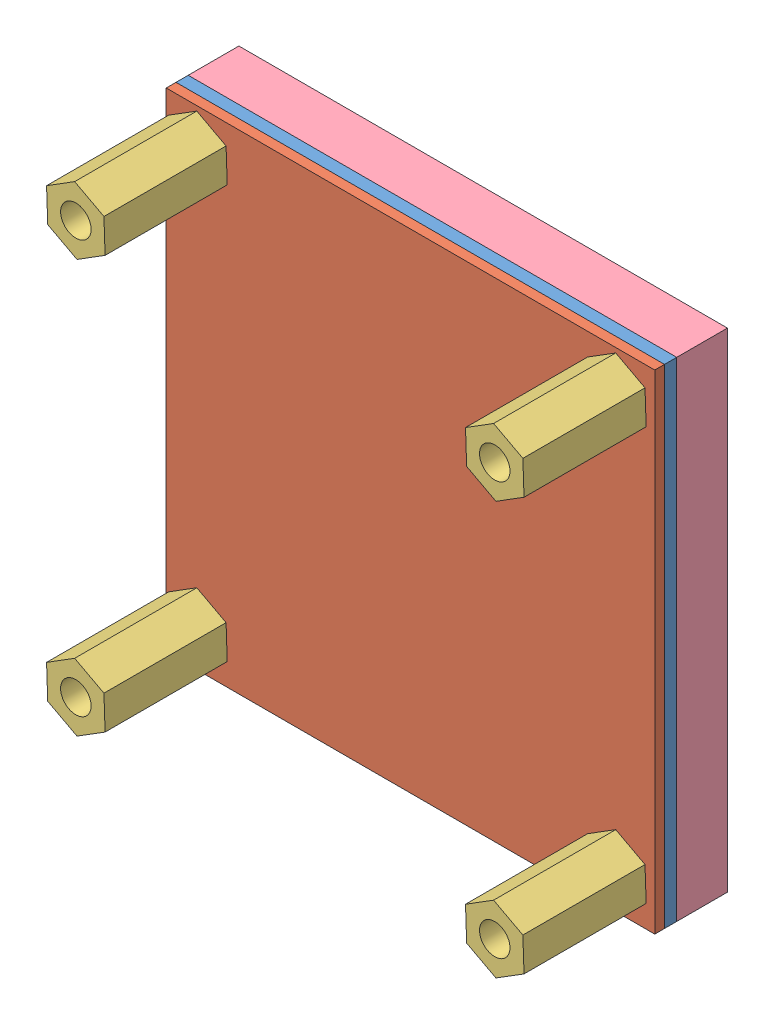
SolidWorks assembly EPM688_V2, configuration Default. Lengths in mm.
Overall size (40 40 16).
7 component instances, 4 part files, 14 mates.
Components (placement in the parent):
- 1559_B-1: 1559_B [Default] at (8.4797 17.3877 36.4763) size (40 40 1)
- pcb-1: pcb [Default] at (8.4797 17.3877 37.4763) size (40 40 0.8)
- standoff-1: standoff [Default] at (-8.9203 34.2877 48.2763) x (-1 0 0) z (0 0 -1) size (4.79 5.42 10)
- standoff-2: standoff [Default] at (-8.9203 0.4877 48.2763) x (-1 0 0) z (0 0 -1) size (4.79 5.42 10)
- standoff-3: standoff [Default] at (25.3797 34.2877 48.2763) x (-1 0 0) z (0 0 -1) size (4.79 5.42 10)
- standoff-4: standoff [Default] at (25.3797 0.4877 48.2763) x (-1 0 0) z (0 0 -1) size (4.79 5.42 10)
- asasdfsdaf-1: asasdfsdaf [Default] at (8.4797 17.3877 36.4763) x (1 0 0) z (0 0 -1) size (40 40 4.2)
Mates (geometry in assembly coordinates):
- Coincident1: coincident anti-aligned: plane of 1559_B-1 through (8.4797 17.3877 37.4763) normal (0 0 1); plane of pcb-1 through (8.4797 17.3877 37.4763) normal (0 0 -1)
- Coincident2: coincident aligned: plane of 1559_B-1 through (-11.5203 -2.6123 37.4763) normal (0 -1 0); plane of pcb-1 through (-11.5203 -2.6123 38.2763) normal (0 -1 0)
- Coincident3: coincident aligned: plane of 1559_B-1 through (28.4797 37.3877 37.4763) normal (1 0 0); plane of pcb-1 through (28.4797 37.3877 38.2763) normal (1 0 0)
- Coincident4: coincident anti-aligned: plane of pcb-1 through (8.4797 17.3877 38.2763) normal (0 0 1); plane of standoff-1 through (-8.9203 34.2877 38.2763) normal (0 0 -1)
- Concentric1: concentric aligned: circle of 1559_B-1; cylinder of standoff-1 through (-8.9203 34.2877 43.2763) axis (0 0 1) radius 1.25
- Coincident5: coincident anti-aligned: plane of pcb-1 through (8.4797 17.3877 38.2763) normal (0 0 1); plane of standoff-2 through (-8.9203 0.4877 38.2763) normal (0 0 -1)
- Concentric2: concentric aligned: circle of 1559_B-1; cylinder of standoff-2 through (-8.9203 0.4877 43.2763) axis (0 0 1) radius 1.25
- Coincident6: coincident anti-aligned: plane of pcb-1 through (8.4797 17.3877 38.2763) normal (0 0 1); plane of standoff-3 through (25.3797 34.2877 38.2763) normal (0 0 -1)
- Concentric3: concentric aligned: circle of 1559_B-1; cylinder of standoff-3 through (25.3797 34.2877 43.2763) axis (0 0 1) radius 1.25
- Coincident7: coincident anti-aligned: plane of pcb-1 through (8.4797 17.3877 38.2763) normal (0 0 1); plane of standoff-4 through (25.3797 0.4877 38.2763) normal (0 0 -1)
- Concentric4: concentric aligned: circle of 1559_B-1; cylinder of standoff-4 through (25.3797 0.4877 43.2763) axis (0 0 1) radius 1.25
- Coincident8: coincident: plane of 1559_B-1 through (8.4797 17.3877 36.4763) normal (0 0 -1); plane of asasdfsdaf-1 through (8.4797 17.3877 36.4763) normal (0 0 1)
- Coincident9: coincident: plane of 1559_B-1 through (-11.5203 -2.6123 37.4763) normal (0 -1 0); plane of asasdfsdaf-1 through (-11.5203 -2.6123 32.3263) normal (0 -1 0)
- Coincident10: coincident aligned: plane of 1559_B-1 through (28.4797 37.3877 37.4763) normal (1 0 0); plane of asasdfsdaf-1 through (28.4797 -2.6123 32.3263) normal (1 0 0)
